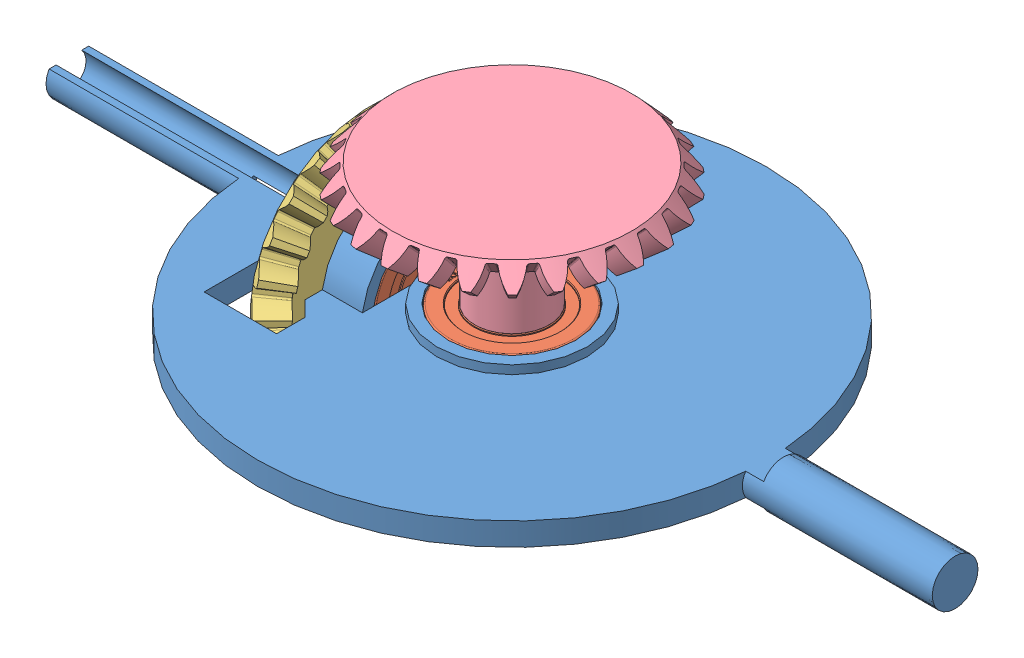
SolidWorks assembly Ball, configuration Default. Lengths in mm.
Overall size (154.9 50.27 88.9).
6 component instances, 5 part files, 12 mates.
Components (placement in the parent):
- Plate-1: Plate [Default] at origin size (154.9 26.3 88.9)
- 608-1: 608 [Default] at (0 3.5 0) x (0 1 0) z (0 0 1) size (7 22 22)
- 608-2: 608 [Default] at (-13.15 0 0) size (7 22 22)
- YawShaft2-2: YawShaft2 [Metric - Straight bevel gear 1.75M 26GT 24PT 20PA 5FW ---26O8H10MD5N] at (-24.8676 0 0) x (1 0 0) z (0 0.056641 0.998395) size (11.72 47.64 47.86)
- Ball_V9_final_Top-1: Ball_V9_final_Top [Default] at origin size (88.8 42.45 88.81) (hidden)
- BallShaft2-1: BallShaft2 [Metric - Straight bevel gear 1.75M 26GT 24PT 20PA 5FW ---26O8H10MD5N] at (0 24.8676 0) x (0 -1 0) z (0.299679 0 0.95404) size (28.37 47.64 47.86)
Mates (geometry in assembly coordinates):
- Concentric2: concentric: cylinder of Plate-1 through (0 3.5 0) axis (0 -1 0) radius 11.15; cylinder of 608-1 through (0 3.5 0) axis (0 1 0) radius 11
- Width1: width: plane of 608-1 through (-8.505 -3.5 0) normal (0 -1 0); plane of 608-1 through (-8.505 3.5 0) normal (0 1 0); plane of Plate-1 through (0 3.5 0) normal (0 1 0); plane of Plate-1 through (0 -3.5 0) normal (0 -1 0)
- Lock1: lock: unknown of Plate-1; unknown of 608-1
- Concentric5: concentric: cylinder of Plate-1 through (-20.15 0 0) axis (1 0 0) radius 11.15; cylinder of 608-2 through (-13.15 0 0) axis (1 0 0) radius 11
- Width2: width: plane of 608-2 through (-20.15 8.505 0) normal (-1 0 0); plane of 608-2 through (-13.15 8.505 0) normal (1 0 0); plane of Plate-1 through (-13.15 0 0) normal (1 0 0); plane of Plate-1 through (-20.15 0 0) normal (-1 0 0)
- Tangent1: tangent: cylinder of Plate-1 through (0 3.5 0) axis (0 -1 0) radius 13.15; plane of YawShaft2-2 through (-13.15 0 0) normal (1 0 0)
- Concentric6: concentric: circle of Plate-1; circle of YawShaft2-2
- Coincident3: coincident: plane of Plate-1 through (0 2 0) normal (0 1 0); plane of Ball_V9_final_Top-1 through (0 2 0) normal (0 -1 0)
- Concentric7: concentric: circle of Plate-1; circle of Ball_V9_final_Top-1
- Concentric8: concentric: circle of Plate-1; circle of BallShaft2-1
- Distance2: distance = 24.8676 mm: plane of BallShaft2-1 through (0 24.8676 0) normal (0 1 0); point of assembly
- GearMate1: gear = 8 : 8 mm: cylinder of BallShaft2-1 through (0 -14.8848 0) axis (0 1 0) radius 6.5; cylinder of YawShaft2-2 through (-13.15 0 0) axis (-1 0 0) radius 4
